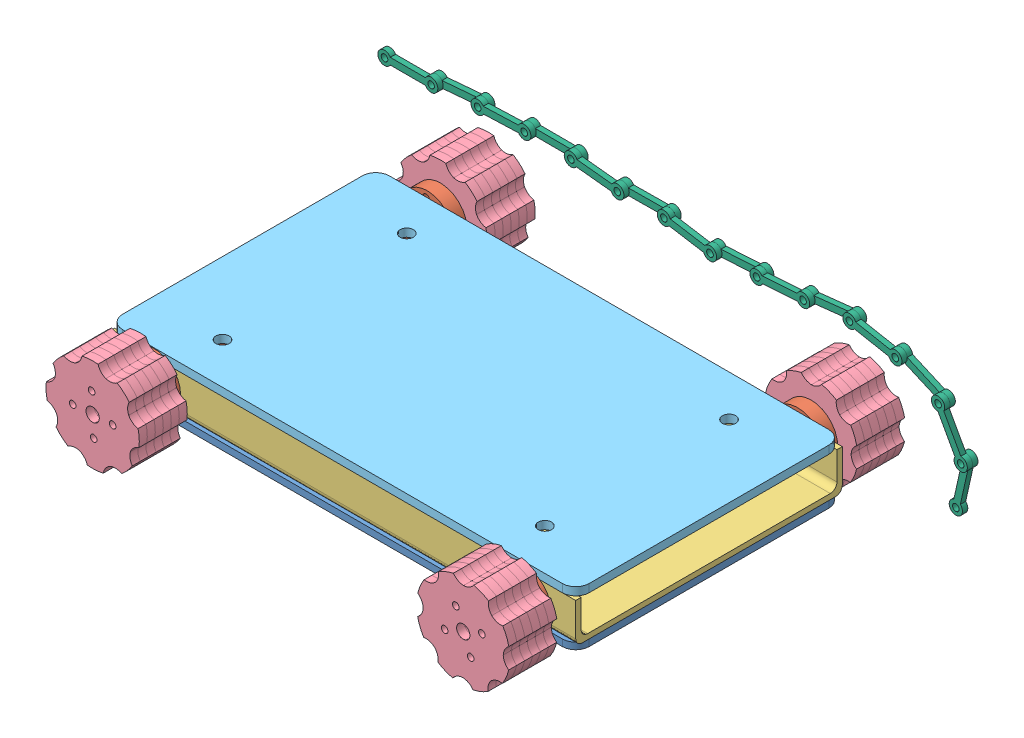
SolidWorks assembly Assem1, configuration Default. Lengths in mm.
Overall size (444.12 104.35 322.3).
45 component instances, 6 part files, 0 mates.
Components (placement in the parent):
- robot-1: robot [Default] at (23.445 30.3428 102.7914) size (444.12 104.35 322.3)
  - base-1: base [Default] at (85.4392 139.2891 312.3541) x (0 0 1) z (0 1 0) size (200 350 5)
  - shaft-1: shaft [Default] at (-39.5608 161.2891 308.8259) x (0.053064 -0.998591 0) z (0 0 1) size (40 40 225)
  - shaft-2: shaft [Default] at (240.4392 161.2891 310.7666) x (0.371711 -0.928348 0) z (0 0 1) size (40 40 225)
  - secondBase-1: secondBase [Default] at (-74.5608 144.2891 412.3541) x (0 0 -1) z (1 0 0) size (200 30 350)
  - belt-1: belt [Default] at (-39.5608 161.2891 423.8259) x (0.053064 -0.998591 0) z (0 0 1) size (70 70 6)
  - belt-2: belt [Default] at (240.4392 161.2891 425.7666) x (0.371711 -0.928348 0) z (0 0 1) size (70 70 6)
  - belt-3: belt [Default] at (-39.5608 161.2891 192.8259) x (-0.998591 -0.053064 0) z (0 0 1) size (70 70 6)
  - belt-4: belt [Default] at (240.4392 161.2891 194.7666) x (0.371711 -0.928348 0) z (0 0 1) size (70 70 6)
  - belt-5: belt [Default] at (-39.5608 161.2891 180.8259) x (-0.998591 -0.053064 0) z (0 0 1) size (70 70 6)
  - belt-6: belt [Default] at (-39.5608 161.2891 186.8259) x (-0.998591 -0.053064 0) z (0 0 1) size (70 70 6)
  - belt-7: belt [Default] at (-39.5608 161.2891 168.8259) x (0.053064 -0.998591 0) z (0 0 1) size (70 70 6)
  - belt-8: belt [Default] at (-39.5608 161.2891 174.8259) x (-0.998591 -0.053064 0) z (0 0 1) size (70 70 6)
  - belt-9: belt [Default] at (240.4392 161.2891 188.7666) x (-0.928348 -0.371711 0) z (0 0 1) size (70 70 6)
  - belt-10: belt [Default] at (240.4392 161.2891 182.7666) x (-0.928348 -0.371711 0) z (0 0 1) size (70 70 6)
  - belt-11: belt [Default] at (240.4392 161.2891 176.7666) x (-0.928348 -0.371711 0) z (0 0 1) size (70 70 6)
  - belt-12: belt [Default] at (240.4392 161.2891 170.7666) x (-0.928348 -0.371711 0) z (0 0 1) size (70 70 6)
  - belt-13: belt [Default] at (240.4392 161.2891 431.7666) x (0.371711 -0.928348 0) z (0 0 1) size (70 70 6)
  - belt-14: belt [Default] at (240.4392 161.2891 437.7666) x (0.371711 -0.928348 0) z (0 0 1) size (70 70 6)
  - belt-15: belt [Default] at (240.4392 161.2891 443.7666) x (0.371711 -0.928348 0) z (0 0 1) size (70 70 6)
  - belt-16: belt [Default] at (240.4392 161.2891 449.7666) x (0.371711 -0.928348 0) z (0 0 1) size (70 70 6)
  - belt-17: belt [Default] at (-39.5608 161.2891 429.8259) x (0.053064 -0.998591 0) z (0 0 1) size (70 70 6)
  - belt-18: belt [Default] at (-39.5608 161.2891 435.8259) x (-0.998591 -0.053064 0) z (0 0 1) size (70 70 6)
  - belt-19: belt [Default] at (-39.5608 161.2891 441.8259) x (0.053064 -0.998591 0) z (0 0 1) size (70 70 6)
  - belt-20: belt [Default] at (-39.5608 161.2891 447.8259) x (0.053064 -0.998591 0) z (0 0 1) size (70 70 6)
  - belt-21: belt [Default] at (-39.5608 161.2891 453.8259) x (0.053064 -0.998591 0) z (0 0 1) size (70 70 6)
  - belt-22: belt [Default] at (240.4392 161.2891 455.7666) x (0.371711 -0.928348 0) z (0 0 1) size (70 70 6)
  - belt-23: belt [Default] at (240.4392 161.2891 164.7666) x (-0.928348 -0.371711 0) z (0 0 1) size (70 70 6)
  - belt-24: belt [Default] at (-39.5608 161.2891 162.8259) x (0.053064 -0.998591 0) z (0 0 1) size (70 70 6)
  - top-1: top [Default] at (100.4392 180.2891 312.3541) x (0 0 -1) z (0 -1 0) size (200 350 6)
  - chain-1: chain [Default] at (-225.8396 157.0049 133.5416) size (444.12 97.37 8)
    - chainPart-1: chainPart [Default] at (92.9067 33.2306 9.9294) size (45 10 4)
    - chainPart-2: chainPart [Default] at (127.9067 33.2306 5.9294) x (0.99643 0.084419 0) z (0 0 1) size (45 10 4)
    - chainPart-3: chainPart [Default] at (162.7817 36.1852 9.9294) x (0.999358 0.03582 0) z (0 0 1) size (45 10 4)
    - chainPart-4: chainPart [Default] at (197.7593 37.4389 5.9294) x (0.999994 -0.003474 0) z (0 0 1) size (45 10 4)
    - chainPart-5: chainPart [Default] at (232.7591 37.3173 9.9294) x (0.994631 -0.103489 0) z (0 0 1) size (45 10 4)
    - chainPart-6: chainPart [Default] at (267.5711 33.6952 5.9294) x (0.999959 0.009082 0) z (0 0 1) size (45 10 4)
    - chainPart-7: chainPart [Default] at (302.5697 34.0131 9.9294) x (0.986781 -0.162057 0) z (0 0 1) size (45 10 4)
    - chainPart-8: chainPart [Default] at (337.107 28.3411 5.9294) x (0.99823 0.059469 0) z (0 0 1) size (45 10 4)
    - chainPart-9: chainPart [Default] at (372.0451 30.4225 9.9294) x (0.997633 0.06876 0) z (0 0 1) size (45 10 4)
    - chainPart-10: chainPart [Default] at (406.9623 32.8291 5.9294) x (0.99408 0.108649 0) z (0 0 1) size (45 10 4)
    - chainPart-11: chainPart [Default] at (441.7551 36.6318 9.9294) x (0.982626 -0.185597 0) z (0 0 1) size (45 10 4)
    - chainPart-12: chainPart [Default] at (476.147 30.1359 5.9294) x (0.916872 -0.399181 0) z (0 0 1) size (45 10 4)
    - chainPart-13: chainPart [Default] at (508.2375 16.1646 9.9294) x (0.48532 -0.874336 0) z (0 0 1) size (45 10 4)
    - chainPart-14: chainPart [Default] at (525.2237 -14.4372 5.9294) x (-0.217955 -0.975959 0) z (0 0 1) size (45 10 4)
